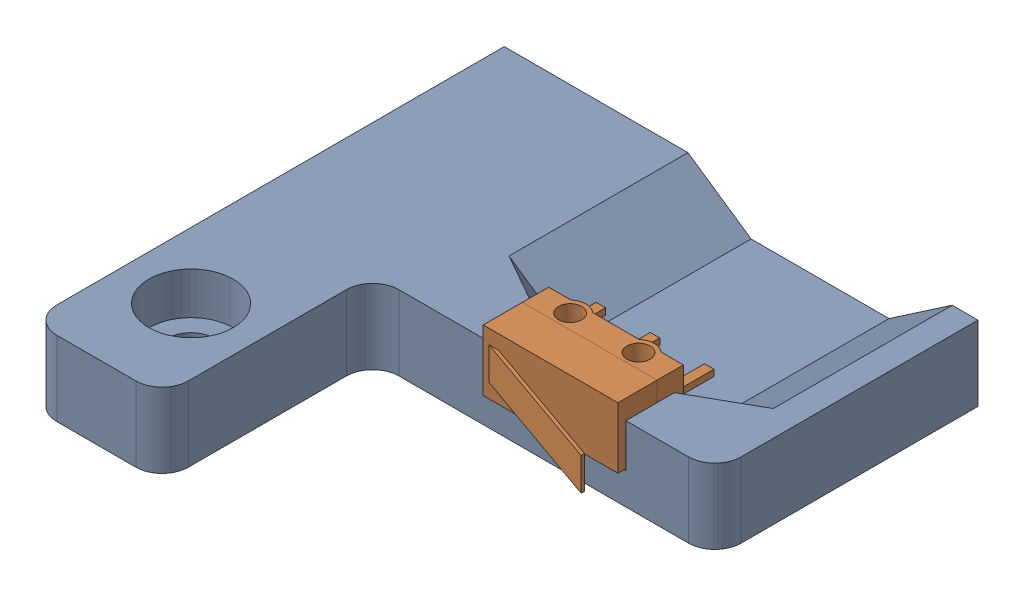
SolidWorks assembly UpperEndStop_Z, configuration Default. Lengths in mm.
Overall size (45 13.8 45).
2 component instances, 2 part files, 3 mates.
Components (placement in the parent):
- WW0016-1: WW0016 [Default] at origin size (45 12.1 45)
- Limit Switch-1: Limit Switch [Default] at (23.6 3 -19.4) x (-1 0 0) z (0 0 -1) size (14.05 5.8 14.66)
Mates (geometry in assembly coordinates):
- Coincident1: coincident anti-aligned: plane of WW0016-1 through (0 3 0) normal (0 1 0); plane of Limit Switch-1 through (23.6 3 -25.62) normal (0 -1 0)
- Width1: width anti-aligned: plane of Limit Switch-1 through (36.4 3 -25.62) normal (1 0 0); plane of WW0016-1 through (23.6 3 -25.62) normal (-1 0 0); plane of Limit Switch-1 through (36.55 3 -20) normal (-1 0 0); plane of WW0016-1 through (23.45 3 -20) normal (1 0 0)
- Concentric1: concentric anti-aligned: cylinder of WW0016-1 through (33.25 7.1 -24.5) axis (0 1 0) radius 1.65; cylinder of Limit Switch-1 through (33.25 3 -24.5) axis (0 -1 0) radius 1.1
